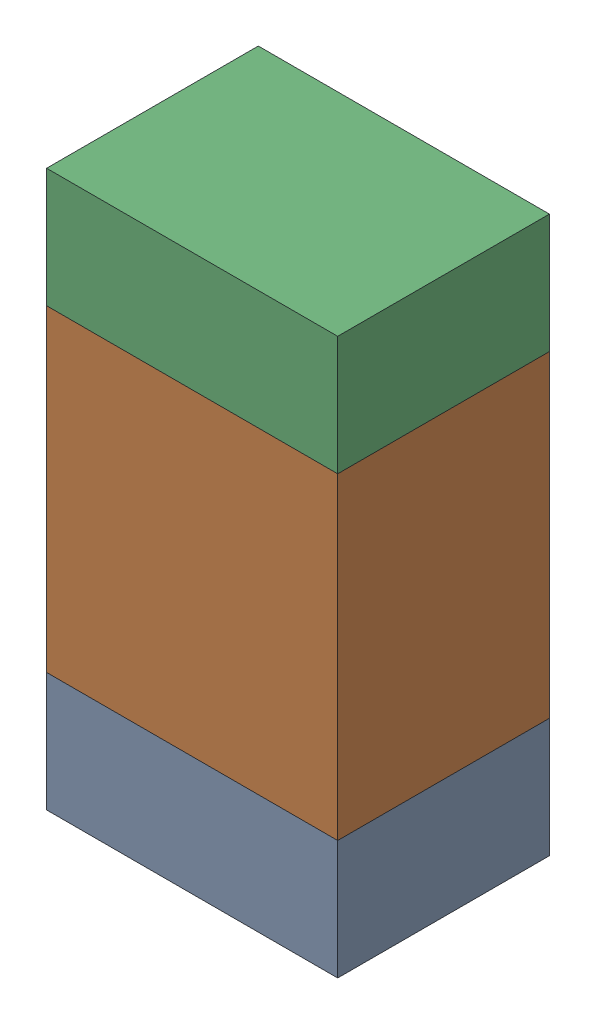
SolidWorks assembly R405PCB, configuration Default. Lengths in mm.
Overall size (0.55 1.05 0.4).
6 component instances, 2 part files, 0 mates.
Components (placement in the parent):
- 846483288-1: 846483288 [Default] at (84.1899 88.4876 0) size (0.55 0.22 0.4)
  - Extruded_12-1: Extruded_12 [Default] at origin size (0.55 0.22 0.4)
- 846483424-1: 846483424 [Default] at (84.1899 88.9001 0) size (0.55 0.6 0.4)
  - Extruded_13-1: Extruded_13 [Default] at origin size (0.55 0.6 0.4)
- 846483288-2: 846483288 [Default] at (84.1899 89.3126 0) size (0.55 0.22 0.4)
  - Extruded_12-1: Extruded_12 [Default] at origin size (0.55 0.22 0.4)
